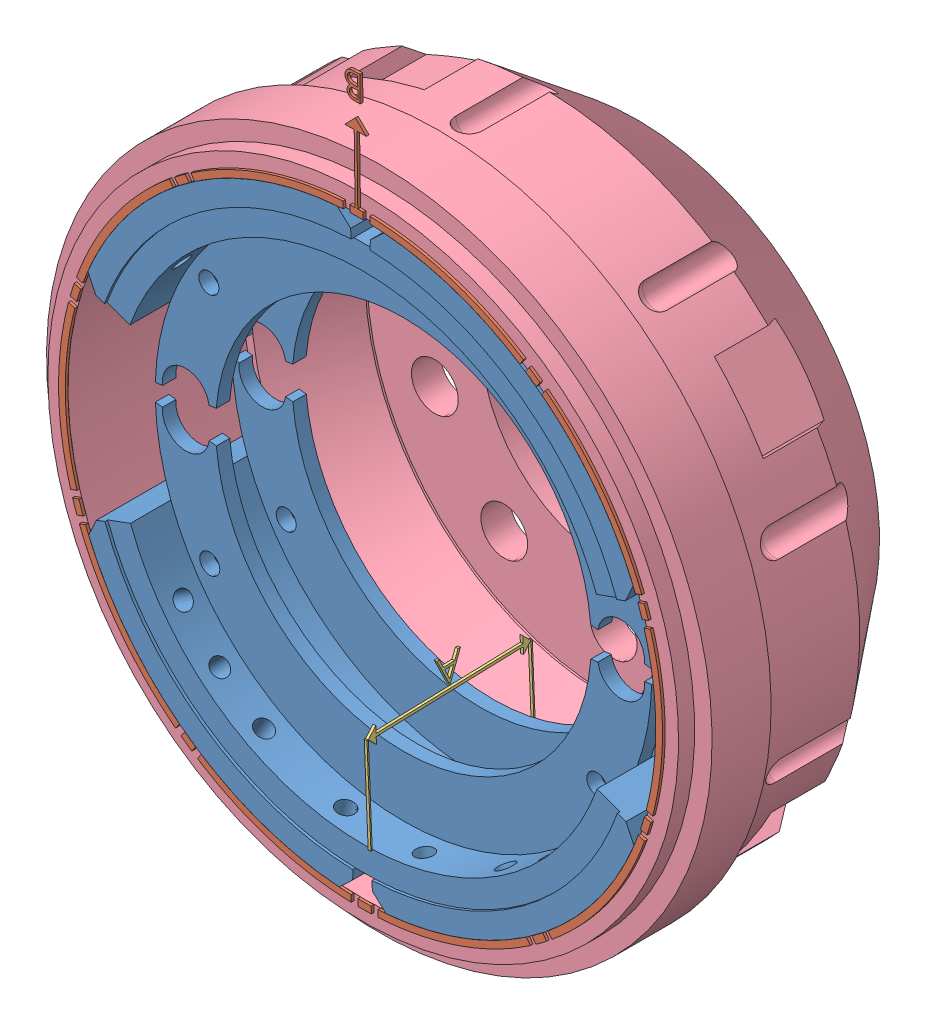
SolidWorks assembly Ensamble Zapata de freno, configuration Predeterminado. Lengths in mm.
Overall size (695.43 695.43 207.06).
5 component instances, 4 part files, 6 mates.
Components (placement in the parent):
- Zapata Nueva-1: Zapata Nueva [Predeterminado] at (11.8922 -74.6973 318.3911) size (406.36 213.65 131)
- Zapata Nueva-2: Zapata Nueva [Predeterminado] at (11.8922 -74.6973 445.3911) x (0.999975 0.007091 0) z (0 0 -1) size (406.36 213.65 131)
- Diametro del tambor-1: Diametro del tambor [Predeterminado] at (11.8922 -74.6973 445.3911) x (-0.999909 -0.013507 0) z (0 0 1) size (450 537.7 2)
- Ancho de zapata-1: Ancho de zapata [Predeterminado] at (17.7646 -259.3581 383.9191) x (-0.029673 -0.001247 -0.999559) z (-0.998677 -0.041967 0.029699) size (127 92.5 2)
- tambor-2: tambor [Predeterminado] at (11.8922 -74.6973 445.3911) x (-0.793466 -0.608615 0) z (0.608615 -0.793466 0) size (496 205 496)
Mates (geometry in assembly coordinates):
- Coincidente1: coincident anti-aligned: circle of Zapata Nueva-1; circle of Zapata Nueva-2
- Distancia1: distance = 10 mm aligned: line of Zapata Nueva-1 through (196.8057 -69.0417 405.3911) axis (0 0 1); line of Zapata Nueva-2 through (196.8412 -79.0416 405.3911) axis (0 0 1)
- Coincidente13: coincident anti-aligned: line of Zapata Nueva-2 through (20.4237 -277.7182 447.3911) axis (0.041986 -0.999118 0); line of Ancho de zapata-1 through (19.6488 -259.2789 447.3911) axis (-0.041986 0.999118 0)
- Paralelo1: parallel anti-aligned: line of Zapata Nueva-2 through (20.4237 -277.7182 316.3911) axis (0.041986 -0.999118 0); line of Ancho de zapata-1 through (15.8803 -259.4373 320.4471) axis (-0.041986 0.999118 0)
- Concéntrica1: concentric aligned: cylinder of Zapata Nueva-2 through (11.8922 -74.6973 316.3911) axis (0 0 1) radius 220; cylinder of tambor-2 through (11.8922 -74.6973 445.3911) axis (0 0 1) radius 220
- Coincidente14: coincident aligned: plane of Zapata Nueva-2 through (11.8922 -74.6973 445.3911) normal (0 0 1); plane of tambor-2 through (145.7875 -249.2598 445.3911) normal (0 0 1)
